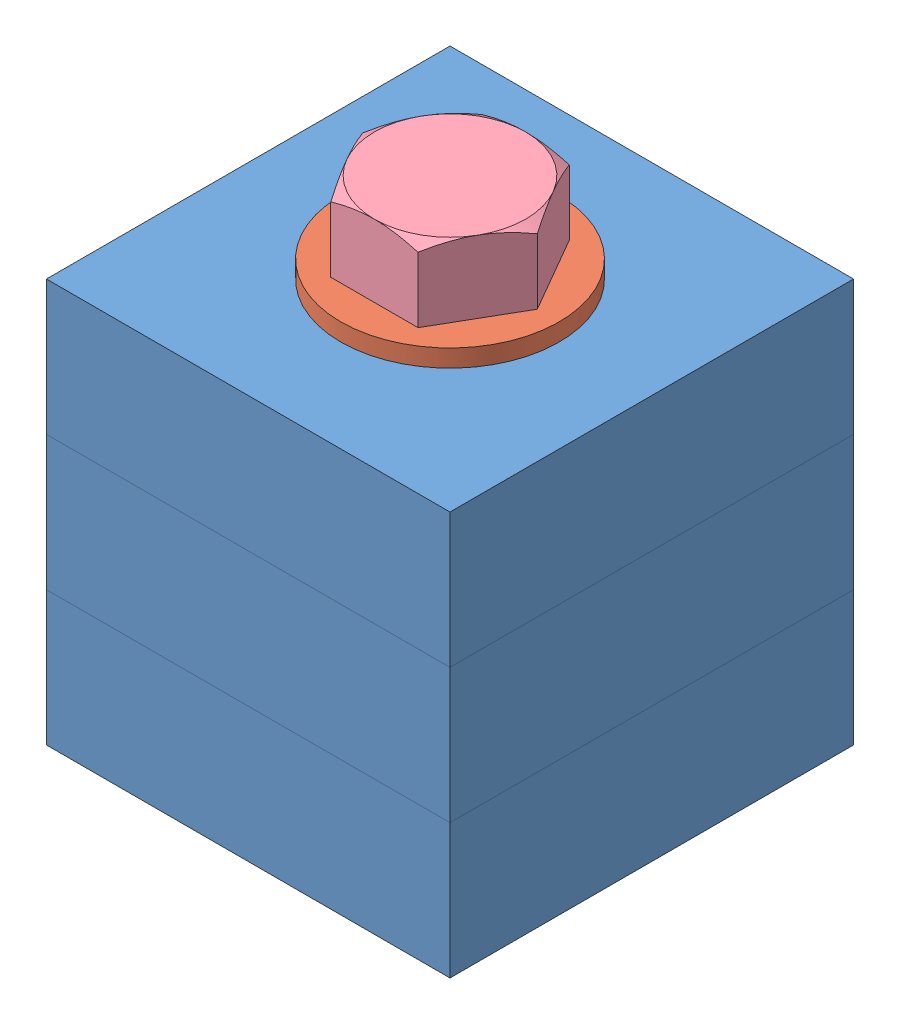
SolidWorks assembly Block -Bolt Assembly, configuration Default. Lengths in mm.
Overall size (38.1 57.61 38.1).
7 component instances, 4 part files, 12 mates.
Components (placement in the parent):
- Block - Bolt v2-1: Block - Bolt v2 [Default] at (3.7793 14.3229 38.5326) size (38.1 12.7 38.1)
- Block - Bolt v2-3: Block - Bolt v2 [Default] at (3.7793 27.0229 38.5326) size (38.1 12.7 38.1)
- Block - Bolt v2-4: Block - Bolt v2 [Default] at (3.7793 39.7229 38.5326) size (38.1 12.7 38.1)
- flat washer type a narrow_ai-1: flat washer type a narrow_ai [Preferred Narrow FW 0.375] at (3.7793 52.4229 38.5326) x (0 -1 0) z (0 0 1) size (1.65 20.62 20.62)
- flat washer type a narrow_ai-2: flat washer type a narrow_ai [Preferred Narrow FW 0.375] at (3.7793 12.6719 38.5326) x (0 -1 0) z (0.098379 0 0.995149) size (1.65 20.62 20.62)
- hex jam nut_ai-1: hex jam nut_ai [HJNUT 0.3750-16-D-N] at (3.7793 12.6719 38.5326) x (0.998549 0 0.053853) z (0 1 0) size (14.27 16.48 5.77)
- hex bolt_ai-1: hex bolt_ai [HBOLT 0.3750-16x2x1-N] at (3.7793 60.8811 38.5326) x (0 -1 0) z (0 0 1) size (57.61 16.48 14.27)
Mates (geometry in assembly coordinates):
- Coincident2: coincident aligned: line of Block - Bolt v2-1 through (22.8293 27.0229 57.5826) axis (0 0 -1); line of Block - Bolt v2-3 through (22.8293 27.0229 57.5826) axis (0 0 -1)
- Coincident3: coincident aligned: line of Block - Bolt v2-1 through (-15.2707 27.0229 57.5826) axis (1 0 0); line of Block - Bolt v2-3 through (-15.2707 27.0229 57.5826) axis (1 0 0)
- Coincident4: coincident aligned: line of Block - Bolt v2-3 through (-15.2707 39.7229 57.5826) axis (1 0 0); line of Block - Bolt v2-4 through (-15.2707 39.7229 57.5826) axis (1 0 0)
- Coincident5: coincident aligned: line of Block - Bolt v2-3 through (-15.2707 39.7229 19.4826) axis (0 0 1); line of Block - Bolt v2-4 through (-15.2707 39.7229 19.4826) axis (0 0 1)
- Concentric1: concentric aligned: cylinder of Block - Bolt v2-4 through (3.7793 39.7219 38.5326) axis (0 1 0) radius 5.588; cylinder of flat washer type a narrow_ai-1 through (3.7793 87.3479 38.5326) axis (0 1 0) radius 5.1562
- Coincident6: coincident anti-aligned: plane of Block - Bolt v2-4 through (3.7793 52.4229 38.5326) normal (0 1 0); plane of flat washer type a narrow_ai-1 through (8.9355 52.4229 38.5326) normal (0 -1 0)
- Concentric2: concentric aligned: cylinder of Block - Bolt v2-1 through (3.7793 14.3219 38.5326) axis (0 1 0) radius 5.588; circle of flat washer type a narrow_ai-2
- Coincident7: coincident anti-aligned: plane of Block - Bolt v2-1 through (3.7793 14.3229 38.5326) normal (0 -1 0); plane of flat washer type a narrow_ai-2 through (14.0417 14.3229 37.5181) normal (0 1 0)
- Concentric4: concentric aligned: circle of flat washer type a narrow_ai-2; circle of hex jam nut_ai-1
- Coincident9: coincident anti-aligned: plane of flat washer type a narrow_ai-2 through (8.9105 12.6719 38.0253) normal (0 -1 0); plane of hex jam nut_ai-1 through (4.2231 12.6719 30.303) normal (0 1 0)
- Concentric5: concentric aligned: cylinder of Block - Bolt v2-4 through (3.7793 39.7219 38.5326) axis (0 1 0) radius 5.588; cylinder of hex bolt_ai-1 through (3.7793 60.8811 38.5326) axis (0 1 0) radius 4.7625
- Coincident10: coincident anti-aligned: plane of flat washer type a narrow_ai-1 through (14.0917 54.0739 38.5326) normal (0 1 0); plane of hex bolt_ai-1 through (12.0209 54.0739 38.5326) normal (0 -1 0)
